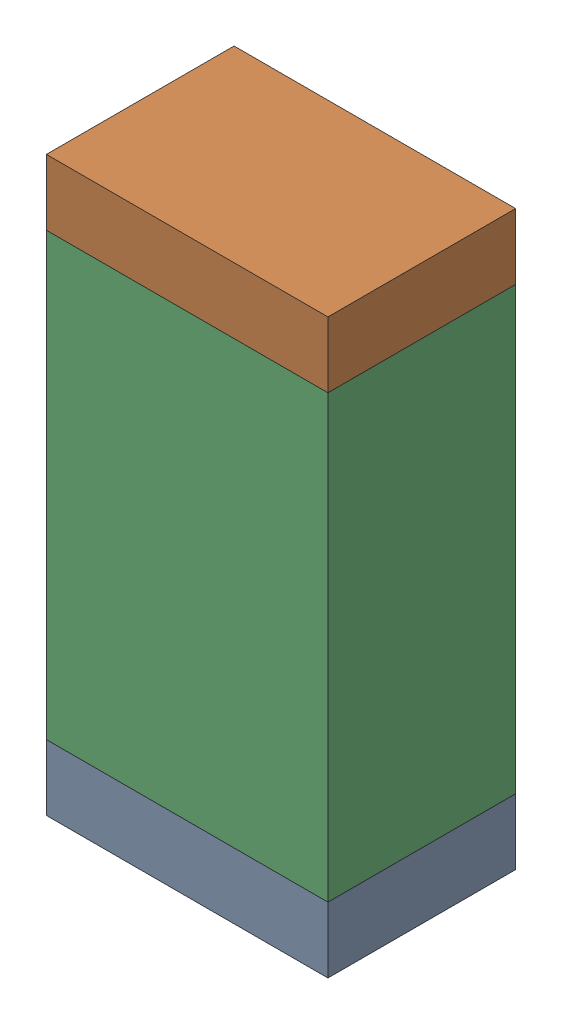
SolidWorks assembly R3, configuration Default. Lengths in mm.
Overall size (0.76 1.55 0.51).
6 component instances, 2 part files, 0 mates.
Components (placement in the parent):
- 822501776-1: 822501776 [Default] at (27.5589 13.7335 0) size (0.76 0.18 0.51)
  - Extruded_3-1: Extruded_3 [Default] at origin size (0.76 0.18 0.51)
- 822501776-2: 822501776 [Default] at (27.5589 15.1051 0) size (0.76 0.18 0.51)
  - Extruded_3-1: Extruded_3 [Default] at origin size (0.76 0.18 0.51)
- 822501912-1: 822501912 [Default] at (27.5589 14.4193 0) size (0.76 1.19 0.51)
  - Extruded_4-1: Extruded_4 [Default] at origin size (0.76 1.19 0.51)
